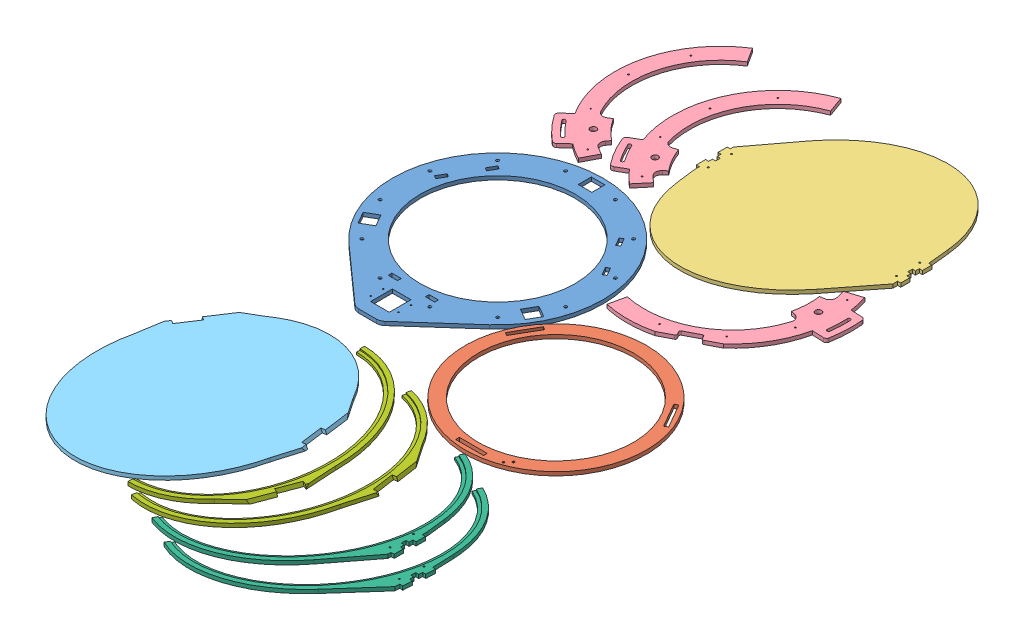
SolidWorks assembly Cutting Layout Sheet 2, configuration Default. Lengths in mm.
Overall size (1353.78 12 2523).
11 component instances, 7 part files, 10 mates.
Components (placement in the parent):
- Base - Bottom Ring-3: Base - Bottom Ring [Default] at origin size (680 12 760)
- Base - Top Ring-1: Base - Top Ring [Default] at (537.8106 70.4648 350.0649) size (585 12 585)
- Mirror Back-1: Mirror Back [Default] at (443.6994 70.4648 -577.1003) size (660 12 719.24)
- Base - Base Ring-2: Base - Base Ring [Section 1] at (277.3467 70.4648 -626.7988) size (259.38 12 579.95)
- Base - Base Ring-3: Base - Base Ring [Section 2] at (61.2217 70.4648 -657.2461) x (-0.676258 0 -0.736665) z (0.736665 0 -0.676258) size (456.29 12 444.04)
- Base - Base Ring-4: Base - Base Ring [Section 3] at (432.4885 70.4648 -325.6301) x (0.886815 0 -0.462124) z (0.462124 0 0.886815) size (575.41 12 280.51)
- Secondary Mirror Back-1: Secondary Mirror Back [Default] at (-38.5734 70.4648 914.5993) x (0.974684 0 0.223588) z (-0.223588 0 0.974684) size (591.82 12 760)
- Mirror Front-1: Mirror Front [Secdtion 1] at (384.5683 82.4648 995.5146) x (0.999961 0 0.008833) z (0.008833 0 -0.999961) size (490.16 12 703.08)
- Mirror Front-2: Mirror Front [Section 2] at (490.5588 82.4648 1053.2859) x (-0.998111 0 -0.061444) z (-0.061444 0 0.998111) size (490.16 12 703.08)
- Secondary Mirror Front-1: Secondary Mirror Front [Section 1] at (204.2975 82.4648 934.6466) x (-0.977362 0 -0.211572) z (-0.211572 0 0.977362) size (296.5 12 760)
- Secondary Mirror Front-2: Secondary Mirror Front [Section 2] at (83.0234 82.4648 894.8898) x (0.999989 0 0.004699) z (0.004699 0 -0.999989) size (296.5 12 760)
Mates (geometry in assembly coordinates):
- Coincident3: coincident aligned: plane of Base - Bottom Ring-3 through (0 82.4648 0) normal (0 1 0); plane of Base - Top Ring-1 through (537.8106 82.4648 350.0649) normal (0 1 0)
- Coincident6: coincident aligned: plane of Base - Bottom Ring-3 through (0 82.4648 0) normal (0 1 0); plane of Mirror Back-1 through (443.6994 82.4648 -577.1003) normal (0 1 0)
- Coincident7: coincident aligned: plane of Base - Bottom Ring-3 through (0 82.4648 0) normal (0 1 0); plane of Base - Base Ring-2 through (277.3467 82.4648 -626.7988) normal (0 1 0)
- Coincident8: coincident aligned: plane of Base - Bottom Ring-3 through (0 82.4648 0) normal (0 1 0); plane of Base - Base Ring-3 through (61.2217 82.4648 -657.2461) normal (0 1 0)
- Coincident9: coincident aligned: plane of Base - Bottom Ring-3 through (0 82.4648 0) normal (0 1 0); plane of Base - Base Ring-4 through (432.4885 82.4648 -325.6301) normal (0 1 0)
- Coincident10: coincident aligned: plane of Base - Bottom Ring-3 through (0 82.4648 0) normal (0 1 0); plane of Secondary Mirror Back-1 through (-38.5734 82.4648 914.5993) normal (0 1 0)
- Coincident11: coincident aligned: plane of Secondary Mirror Back-1 through (-38.5734 82.4648 914.5993) normal (0 1 0); plane of Mirror Front-2 through (490.5588 82.4648 1053.2859) normal (0 1 0)
- Coincident14: coincident aligned: plane of Secondary Mirror Back-1 through (-38.5734 82.4648 914.5993) normal (0 1 0); plane of Mirror Front-1 through (384.5683 82.4648 995.5146) normal (0 1 0)
- Coincident15: coincident aligned: plane of Secondary Mirror Back-1 through (-38.5734 82.4648 914.5993) normal (0 1 0); plane of Secondary Mirror Front-1 through (204.2975 82.4648 934.6466) normal (0 1 0)
- Coincident16: coincident aligned: plane of Secondary Mirror Back-1 through (-38.5734 82.4648 914.5993) normal (0 1 0); plane of Secondary Mirror Front-2 through (83.0234 82.4648 894.8898) normal (0 1 0)
